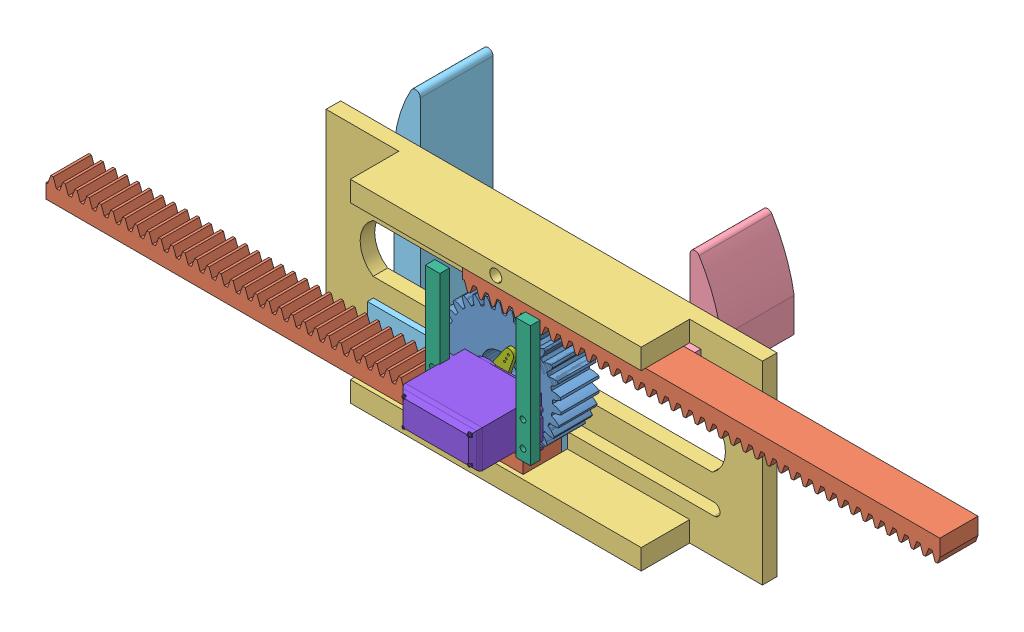
SolidWorks assembly rack & pinion, configuration Default. Lengths in mm.
Overall size (468.32 123.33 130.06).
12 component instances, 8 part files, 27 mates.
Components (placement in the parent):
- spur gear_am-1: spur gear_am [Metric - Spur gear 2M 30T 20PA 20FW ---S30N75H50L20N] at (0 0 -20) x (0 0 1) z (-0.852428 -0.522845 0) size (20 63.76 64)
- rack spur rectangular_am-1: rack spur rectangular_am [Metric - Rack-spur - rectangular 2M 20PA 20FW 10PH 250L---SAll] at (-237.9279 -40 0) size (250 12 20)
- rack spur rectangular_am-4: rack spur rectangular_am [Metric - Rack-spur - rectangular 2M 20PA 20FW 10PH 250L---SAll] at (-19.6115 40.3251 -20) x (1 0 0) z (0 0 -1) size (250 12 20)
- spur gear_am-2: spur gear_am [Metric - Spur gear 2M 30T 20PA 20FW ---S30N75H50L20N] x (0 0 -1) z (-0.026583 0.999647 0) size (20 63.76 64)
- base-1: base [Default] at (-114.3441 -50.6069 -30.795) x (1 0 0) z (0 -1 0) size (228.6 33.02 101.6)
- gripper-3: gripper [Default] at (81.9885 40.3251 -23.175) x (-1 0 0) z (0 1 0) size (101.6 52.07 50.18)
- gripper up-2: gripper up [Default] at (-89.5279 -40 -23.175) x (1 0 0) z (0 -1 0) size (101.6 52.07 112.55)
- servo mount-1: servo mount [Default] at (29.8264 50.9931 16.4887) x (0 0 1) z (1 0 0) size (5.08 63.5 7.62)
- servostuff-1: servostuff [Default] at (-16.229 -5.3828 -20.92) x (0.727827 -0.61737 0.298533) z (-0.263322 0.150355 0.952919) size (63.92 51.4 57.71)
  - hs-422_horn_2wings_sws-1: hs-422_horn_2wings_sws [Default] at (15.3311 15.6503 18.3768) x (0.928495 0.214873 -0.302863) z (-0.220849 0.975196 0.014811) size (9.1 5 34)
  - Standard Servo-1: Standard Servo [Default] at (36.8012 23.6911 54.6372) x (-0.727827 -0.63319 0.263322) z (0.61737 -0.772171 -0.150355) size (53.74 42.63 19.57)
- servo mount-2: servo mount [Default] at (-17.6336 50.9931 16.4887) x (0 0 1) z (1 0 0) size (5.08 63.5 7.62)
Mates (geometry in assembly coordinates):
- Coincident1: coincident aligned: plane of spur gear_am-1 through (0 0 0) normal (0 0 1); plane of assembly through (0 0 0) normal (0 0 1)
- Coincident2: coincident aligned: line of rack spur rectangular_am-1 through (250 -237.9279 -40) axis (0 1 0); line of assembly
- Concentric1: concentric anti-aligned: cylinder of spur gear_am-1 through (0 0 30.0001) axis (0 0 -1) radius 10; circle of assembly
- Coincident3: coincident aligned: plane of spur gear_am-1 through (0 0 -20) normal (0 0 -1); plane of rack spur rectangular_am-1 through (-237.9279 -28 -20) normal (0 0 -1)
- RackPinionMate1: rack pinion = 60 mm: line of rack spur rectangular_am-1 through (250 -237.9279 -40) axis (0 1 0); circle of spur gear_am-1
- Coincident11: coincident aligned: plane of rack spur rectangular_am-4 through (-19.6115 28.3251 0) normal (0 0 1); plane of spur gear_am-2 through (0 0 0) normal (0 0 1)
- RackPinionMate8: rack pinion = 60 mm: line of rack spur rectangular_am-4 through (-19.6115 40.3251 -20) axis (1 0 0); circle of spur gear_am-2
- Coincident13: coincident aligned: plane of spur gear_am-2 through (0 0 0) normal (0 0 1); plane of assembly through (0 0 0) normal (0 0 1)
- Coincident14: coincident aligned: plane of spur gear_am-1 through (0 0 -20) normal (0 0 -1); plane of spur gear_am-2 through (0 0 -20) normal (0 0 -1)
- Coincident15: coincident aligned: circle of spur gear_am-1; circle of spur gear_am-2
- Coincident16: coincident: point of spur gear_am-1; point of spur gear_am-2
- Distance2: distance = 80.3251 mm anti-aligned: plane of rack spur rectangular_am-1 through (-237.9279 -40 -20) normal (0 -1 0); plane of rack spur rectangular_am-4 through (-19.6115 40.3251 0) normal (0 1 0)
- Coincident24: coincident anti-aligned: plane of rack spur rectangular_am-1 through (-237.9279 -28 -20) normal (0 0 -1); plane of gripper up-2 through (-89.5279 -40 -20) normal (0 0 1)
- Coincident25: coincident aligned: plane of rack spur rectangular_am-1 through (-237.9279 -40 -20) normal (0 -1 0); plane of gripper up-2 through (-89.5279 -40 -20) normal (0 -1 0)
- Coincident27: coincident anti-aligned: plane of gripper-3 through (81.9885 40.3251 -20) normal (0 0 1); plane of rack spur rectangular_am-4 through (-19.6115 28.3251 -20) normal (0 0 -1)
- Coincident29: coincident aligned: plane of rack spur rectangular_am-4 through (-19.6115 40.3251 0) normal (0 1 0); plane of gripper-3 through (81.9885 40.3251 -20) normal (0 1 0)
- Coincident32: coincident anti-aligned: plane of base-1 through (-114.3441 -50.6069 -23.175) normal (0 0 1); plane of gripper up-2 through (-89.5279 -40 -23.175) normal (0 0 -1)
- Coincident40: coincident anti-aligned: plane of rack spur rectangular_am-4 through (-19.6115 40.3251 0) normal (0 1 0); plane of base-1 through (76.1559 40.3251 2.225) normal (0 -1 0)
- Distance3: distance = 114.3 mm: point of assembly; line of base-1 through (114.2559 -50.6069 -23.175) axis (0 1 0)
- Coincident43: coincident aligned: plane of rack spur rectangular_am-4 through (-19.6115 40.3251 0) normal (-1 0 0); plane of gripper-3 through (-19.6115 40.3251 -20) normal (-1 0 0)
- Coincident44: coincident aligned: plane of rack spur rectangular_am-1 through (12.0721 -40 -20) normal (1 0 0); plane of gripper up-2 through (12.0721 -40 -20) normal (1 0 0)
- Concentric2: concentric anti-aligned: cylinder of spur gear_am-2 through (0 0 -50.0001) axis (0 0 1) radius 10; cylinder of servostuff-1/hs-422_horn_2wings_sws-1 through (0 0 4.5) axis (0 0 -1) radius 4.5
- Parallel1: parallel aligned: plane of base-1 through (-114.3441 50.9931 -23.175) normal (0 1 0); plane of servostuff-1/Standard Servo-1 through (29.8264 9.785 8.02) normal (0 1 0)
- Coincident48: coincident anti-aligned: plane of spur gear_am-2 through (0 0 0) normal (0 0 1); plane of servostuff-1/hs-422_horn_2wings_sws-1 through (-6.5662 -12.9281 0) normal (0 0 -1)
- Coincident49: coincident aligned: plane of base-1 through (-114.3441 50.9931 -23.175) normal (0 1 0); plane of servo mount-1 through (37.4464 50.9931 16.4887) normal (0 1 0)
- Coincident50: coincident anti-aligned: plane of servo mount-1 through (37.4464 50.9931 16.4887) normal (0 0 -1); plane of servostuff-1/Standard Servo-1 through (36.5364 -9.785 16.4887) normal (0 0 1)
- Coincident51: coincident anti-aligned: plane of servo mount-1 through (29.8264 50.9931 16.4887) normal (-1 0 0); plane of servostuff-1/Standard Servo-1 through (29.8264 9.785 8.02) normal (1 0 0)
